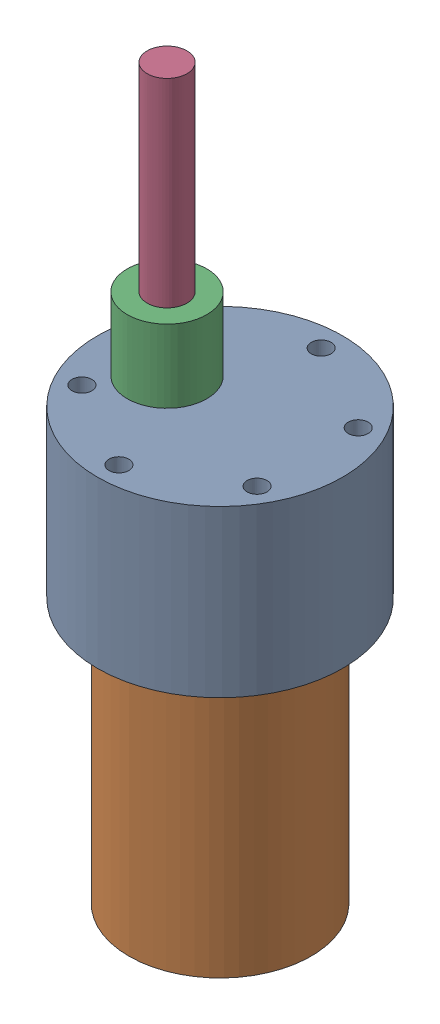
SolidWorks assembly johnsonmotorassembly, configuration Default. Lengths in mm.
Overall size (38.06 106 38.06).
4 component instances, 4 part files, 6 mates.
Components (placement in the parent):
- motorpart1-1: motorpart1 [Default] at (14.245 8.4851 58.0885) size (37 25 37)
- motorpart2-1: motorpart2 [Default] at (14.245 8.4851 58.0885) x (-0.837169 0 -0.546944) z (-0.546944 0 0.837169) size (27.5 40 27.5)
- rotor-1: rotor [Default] at (6.245 44.4851 58.0885) x (-0.659578 0 0.751636) z (0.751636 0 0.659578) size (12 11 12)
- shaftjohnsonmotormadhur-1: shaftjohnsonmotormadhur [Default] at (6.245 44.4851 58.0885) x (-0.014652 0 -0.999893) z (0.999893 0 -0.014652) size (6 30 6)
Mates (geometry in assembly coordinates):
- Concentric1: concentric anti-aligned: circle of motorpart1-1; circle of motorpart2-1
- Coincident1: coincident anti-aligned: plane of motorpart1-1 through (14.245 8.4851 58.0885) normal (0 -1 0); plane of motorpart2-1 through (14.245 8.4851 58.0885) normal (0 1 0)
- Concentric2: concentric anti-aligned: circle of rotor-1
- Coincident3: coincident anti-aligned: plane of motorpart1-1 through (14.245 33.4851 58.0885) normal (0 1 0); plane of rotor-1 through (6.245 33.4851 58.0885) normal (0 -1 0)
- Concentric3: concentric anti-aligned: circle of rotor-1; circle of shaftjohnsonmotormadhur-1
- Coincident4: coincident anti-aligned: plane of rotor-1 through (6.245 44.4851 58.0885) normal (0 1 0); plane of shaftjohnsonmotormadhur-1 through (6.245 44.4851 58.0885) normal (0 -1 0)
